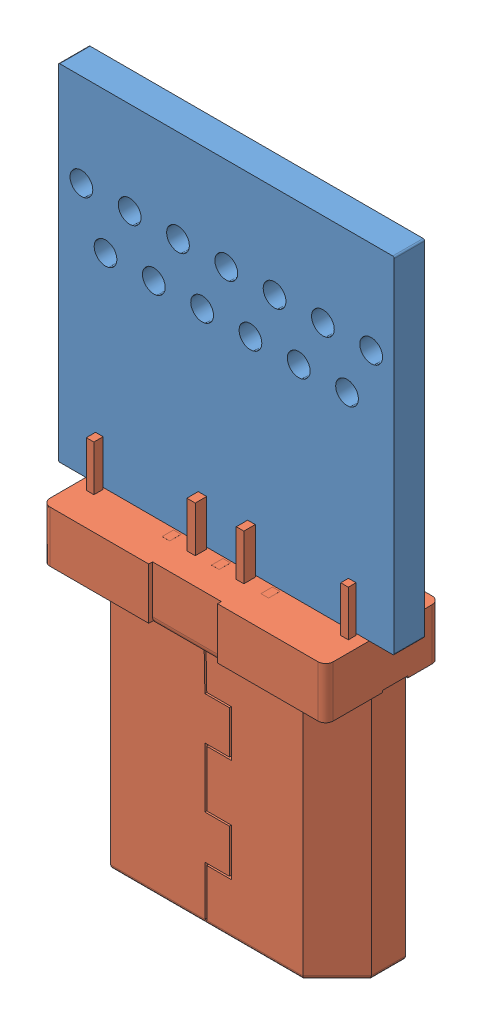
SolidWorks assembly 2457578972UW1 1.0 20230628(1), configuration 默认. Lengths in mm.
Overall size (8.83 17.17 3.2).
4 component instances, 2 part files, 0 mates.
Components (placement in the parent):
- Board-1: Board [默认] at origin size (8.83 9.08 0.8)
  - Open CASCADE STEP translator 6.8 7.1.1-1: Open CASCADE STEP translator 6.8 7.1.1 [默认] at (0 0 -0.8) size (8.83 9.08 0.8)
- Designator22-1: Designator22 [默认] at origin size (7.46 9.25 3.2)
  - micro_usb1-1: micro_usb1 [默认] at (29.8527 75.8913 -1.3) x (1 0 0) z (0 0 -1) size (7.46 9.25 3.2)
